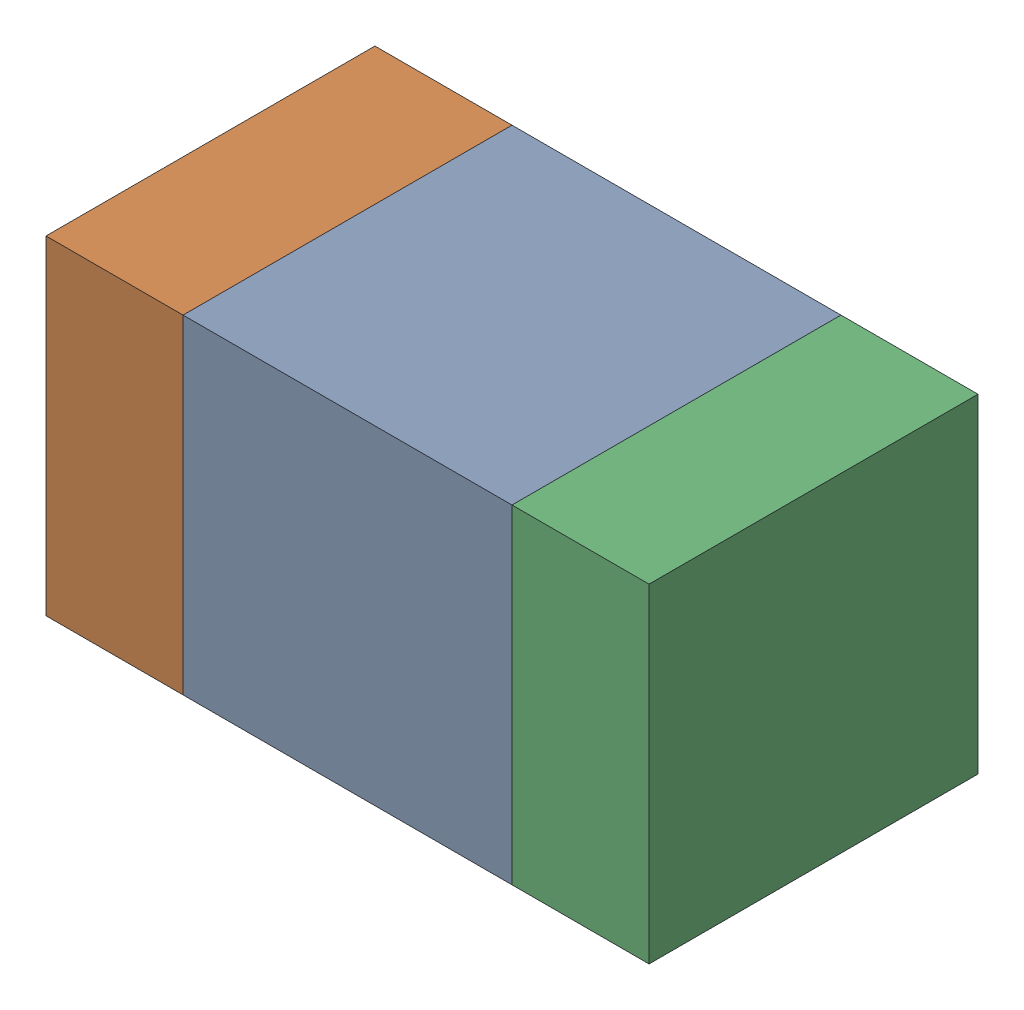
SolidWorks assembly C201PCB, configuration Default. Lengths in mm.
Overall size (1.1 0.6 0.6).
6 component instances, 2 part files, 0 mates.
Components (placement in the parent):
- 761606048-1: 761606048 [Default] at (92.6 124.6 0) size (0.6 0.6 0.6)
  - Extruded_9-1: Extruded_9 [Default] at origin size (0.6 0.6 0.6)
- 854785160-1: 854785160 [Default] at (92.175 124.6 0) size (0.25 0.6 0.6)
  - Extruded_19-1: Extruded_19 [Default] at origin size (0.25 0.6 0.6)
- 854785160-2: 854785160 [Default] at (93.025 124.6 0) size (0.25 0.6 0.6)
  - Extruded_19-1: Extruded_19 [Default] at origin size (0.25 0.6 0.6)
